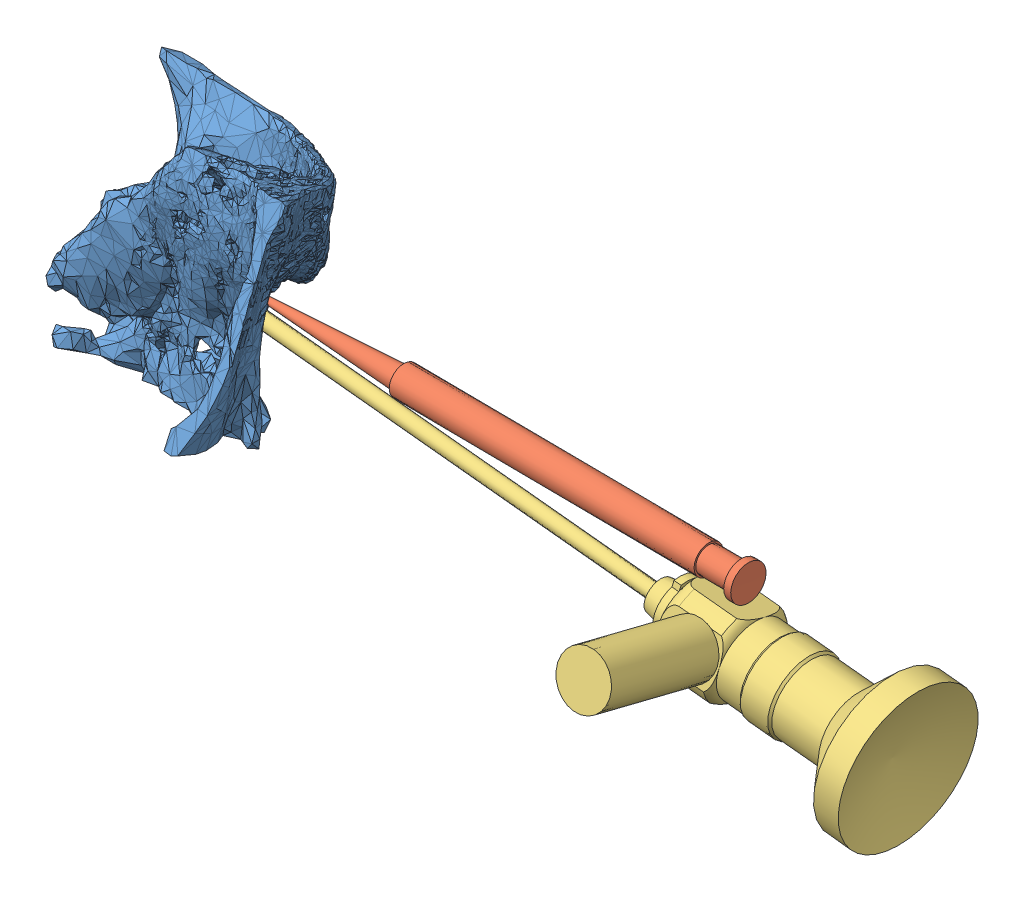
SolidWorks assembly Assem1, configuration Default. Lengths in mm.
Overall size (180.54 64.32 57.5).
3 component instances, 3 part files, 0 mates.
Components (placement in the parent):
- temporal bone_reduced-1: temporal bone_reduced [Default] at (-42607.8597 -23644.7719 43590.026) size (52.78 53.14 44.53)
- Panetti left with tip reach volume-1: Panetti left with tip reach volume [Default] at (4.8646 7.0837 71.5924) x (0.011942 -0.959633 0.281) z (0.999917 0.012837 0.001343) size (8.08 7.5 125.34)
- endoscope-1: endoscope [Default] at (43.708 27.7176 58.8985) x (-0.993079 0.116713 0.013146) z (0.044898 0.273812 0.960735) size (162.79 30 47.5)
